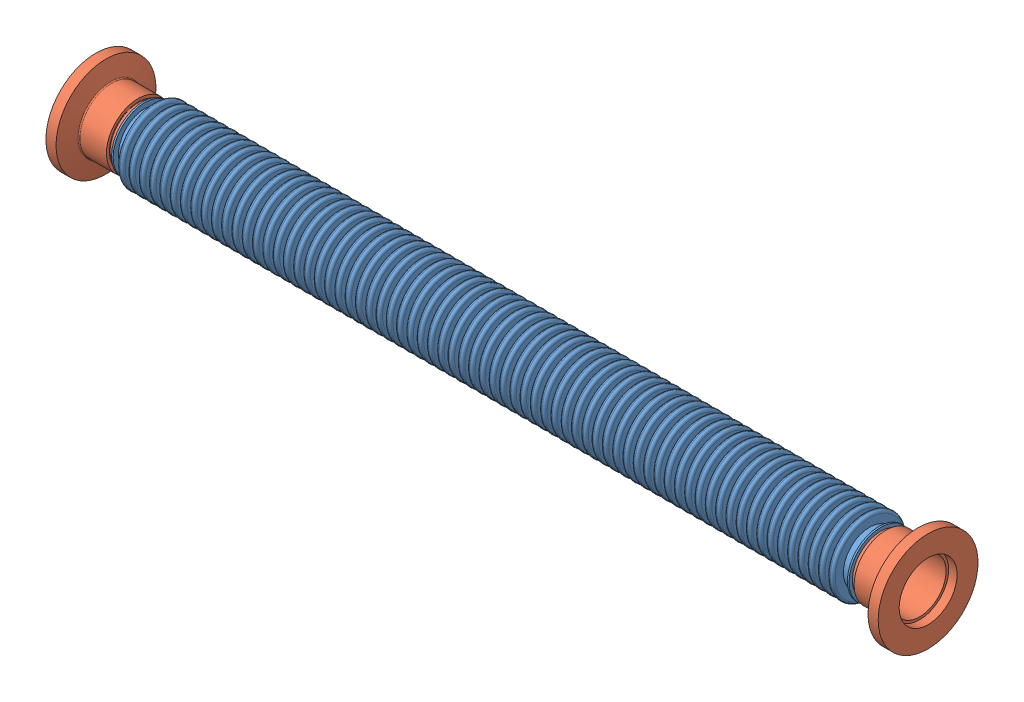
SolidWorks assembly 722020, configuration Default. Lengths in mm.
Overall size (249.94 34.84 34.84).
3 component instances, 2 part files, 4 mates.
Components (placement in the parent):
- SUB02-1: SUB02 [Default] at (42.8305 56.1723 85.3184) size (221.49 22.23 22.23)
- 713001-1: 713001 [Default] at (-82.1375 56.1723 85.3184) x (0 0.178326 -0.983971) z (1 0 0) size (29.97 29.97 14.22)
- 713001-2: 713001 [Default] at (167.7985 56.1723 85.3184) x (0 0 1) z (-1 0 0) size (29.97 29.97 14.22)
Mates (geometry in assembly coordinates):
- Coincident1: coincident anti-aligned: plane of SUB02-1 through (-67.9135 56.1723 85.3184) normal (-1 0 0); plane of 713001-1 through (-67.9135 57.5878 77.5081) normal (1 0 0)
- Concentric1: concentric anti-aligned: cylinder of SUB02-1 through (153.5745 56.1723 85.3184) axis (1 0 0) radius 7.9375; cylinder of 713001-1 through (-82.1375 56.1723 85.3184) axis (-1 0 0) radius 9.525
- Coincident2: coincident anti-aligned: plane of SUB02-1 through (153.5745 56.1723 85.3184) normal (1 0 0); plane of 713001-2 through (153.5745 56.1723 93.2559) normal (-1 0 0)
- Concentric2: concentric aligned: cylinder of SUB02-1 through (153.5745 56.1723 85.3184) axis (1 0 0) radius 7.9375; cylinder of 713001-2 through (167.7985 56.1723 85.3184) axis (1 0 0) radius 9.525
